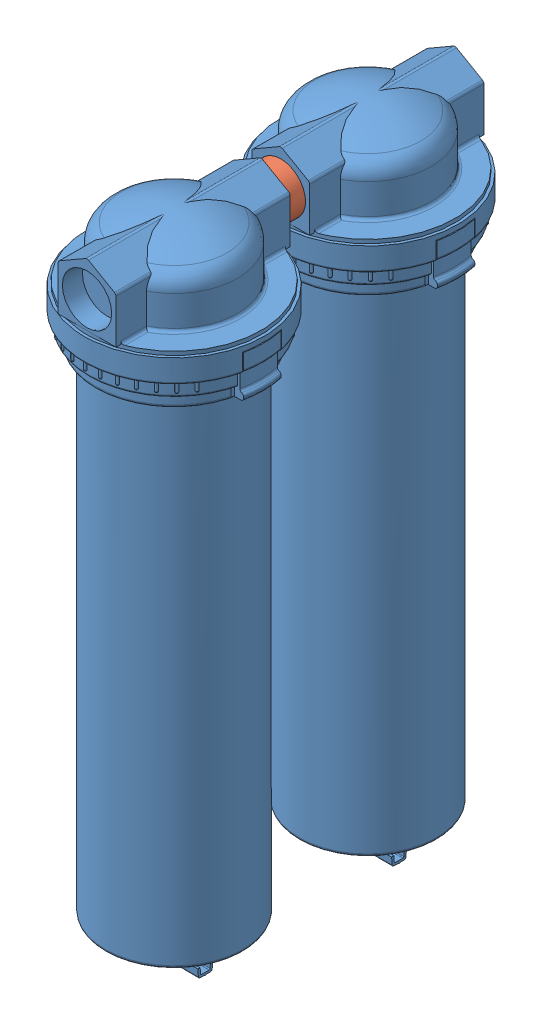
SolidWorks assembly ReadingTech_3P-090-M08-DCP, configuration Default. Lengths in mm.
Overall size (121.86 439.41 252.73).
3 component instances, 2 part files, 3 mates.
Components (placement in the parent):
- ReadingTech_3P-090-M08-P-1: ReadingTech_3P-090-M08-P [Default] at (1.727 -185.5687 -6.2064) size (121.86 439.41 121.67)
- ReadingTech_3P-090-M08-P-2: ReadingTech_3P-090-M08-P [Default] at (1.727 -185.5687 -137.2704) size (121.86 439.41 121.67)
- ReadingTech- 90,150cfm_connector_1in-1: ReadingTech- 90,150cfm_connector_1in [Default] at (1.727 203.4323 -78.3424) x (1 0 0) z (0 -1 0) size (33.4 13.21 33.4)
Mates (geometry in assembly coordinates):
- Coincident1: coincident anti-aligned: circle of ReadingTech_3P-090-M08-P-1; circle of ReadingTech- 90,150cfm_connector_1in-1
- Coincident2: coincident aligned: circle of ReadingTech_3P-090-M08-P-2; circle of ReadingTech- 90,150cfm_connector_1in-1
- Coincident3: coincident aligned: plane of ReadingTech_3P-090-M08-P-1 through (21.285 216.1323 52.7216) normal (1 0 0); plane of ReadingTech_3P-090-M08-P-2 through (21.285 216.1323 -78.3424) normal (1 0 0)
